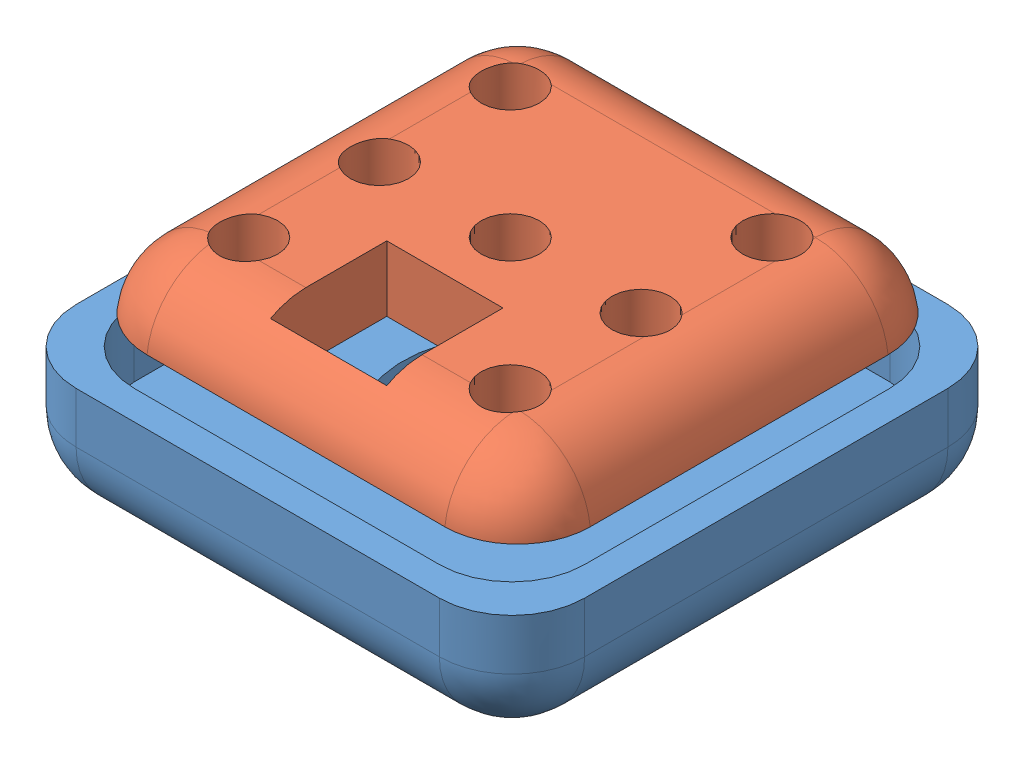
SolidWorks assembly DiceBoxAssembly, configuration Default. Lengths in mm.
Overall size (70 29.88 70).
2 component instances, 2 part files, 0 mates.
Components (placement in the parent):
- DiceBoxBottom-2: DiceBoxBottom [Default] at origin size (70 17 70)
- hjørnetest-1: hjørnetest [Default] at (-0.3857 20.7272 -0.1467) size (61 9.15 61)
